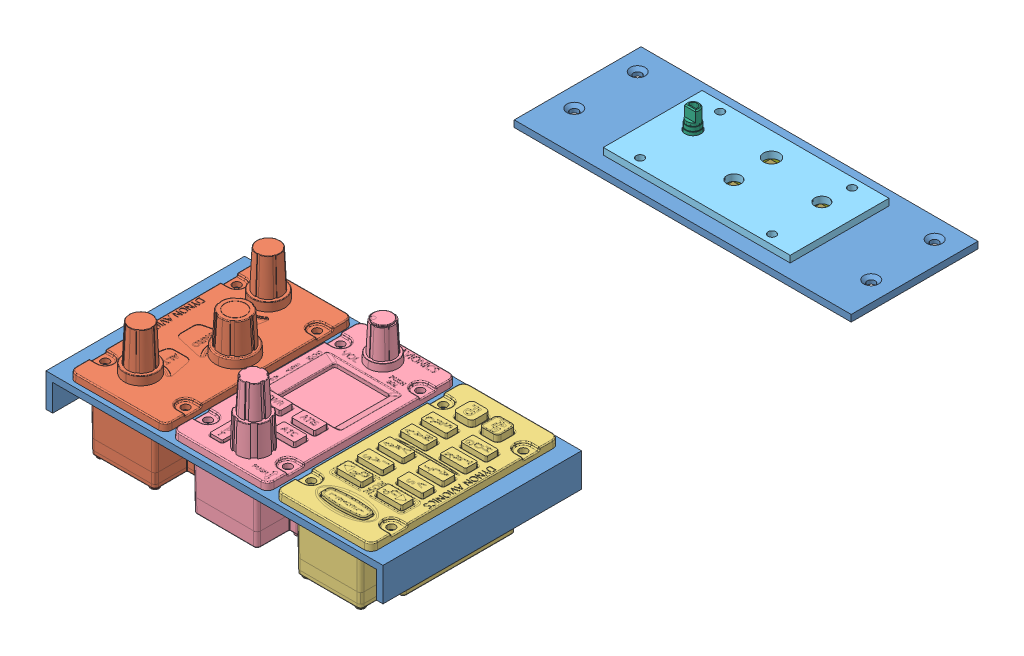
SolidWorks assembly Radio assembly, configuration Default. Lengths in mm.
Overall size (201.11 66.42 309.26).
24 component instances, 17 part files, 8 mates.
Components (placement in the parent):
- Radio stack Bottom-1: Radio stack Bottom [Default] at (52.5504 228.246 225.1405) size (201.11 15.88 309.26)
- SV-KNOB-PANEL_Knob_Control_Panel_Horizontal_Sand_Filled.igs-1: SV-KNOB-PANEL_Knob_Control_Panel_Horizontal_Sand_Filled.igs [Default] at (75.9593 231.421 392.7624) x (0.999994 0 -0.003503) z (0 1 0) size (52.38 89.72 58.92)
- SV-AP-PANEL_Autopilot_Control_Panel_Horizontal_Sand_Filled.igs-1: SV-AP-PANEL_Autopilot_Control_Panel_Horizontal_Sand_Filled.igs [Default] at (174.3711 231.421 393.0909) x (1 0 0) z (0 1 0) size (45.73 89.72 38.5)
- SV-COM-PANEL_Vertical_Solid_Model.igs-1: SV-COM-PANEL_Vertical_Solid_Model.igs [Default] at (101.8389 231.421 437.4175) x (0.999995 0 0.003205) z (0 1 0) size (45.73 89.72 66.42)
- Lighting front plate-1: Lighting front plate [Default] at (52.5504 231.421 225.1405) x (1 0 0) z (0 1 0) size (88.9 46.99 3.17)
- EC12D1524403.step-4: EC12D1524403.step [Default] at (102.1513 226.8481 189.6817) x (1 0 0) z (0 1 0) size (14.15 12.96 20.98)
- untitled.step-1: untitled.step [Default] at (88.9882 225.2956 173.1478) x (0 0 1) z (0 1 0) size (36.53 79.25 3.18)
  - Packages.step-1: Packages.step [Default] at origin size (35.84 78.38 3.18)
    - 78XXL.step-1: 78XXL.step [Default] at (16.51 28.448 -0.0525) x (0 -1 0) z (0 0 -1) size (6.6 3.05 1.47)
    - 32A_ATM.step-1: 32A_ATM.step [Default] at (16.764 58.42 -0.0525) x (0 1 0) z (0 0 -1) size (10.48 11.01 0.1)
    - PINHEADER_2R03_100MIL.step-1: PINHEADER_2R03_100MIL.step [Default] at (4.064 55.626 -0.0525) x (0 -1 0) z (0 0 -1) size (7.77 5.23 0.1)
    - F09V.step-1: F09V.step [Default] at (30.988 66.802 -0.0525) x (0 1 0) z (0 0 -1) size (32.16 12.6 0.1)
    - F09V.step-2: F09V.step [Default] at (30.988 20.574 -0.0525) x (0 1 0) z (0 0 -1) size (32.16 12.6 0.1)
    - C1206.step-1: C1206.step [Default] at (21.082 22.098 -0.0525) x (-1 0 0) z (0 0 -1) size (3.2 1.6 1.3)
    - C1206.step-2: C1206.step [Default] at (21.082 33.528 -0.0525) x (1 0 0) z (0 0 -1) size (3.2 1.6 1.3)
    - EC12S.step-1: EC12S.step [Default] at (15.494 73.66 1.5525) x (0 -1 0) z (0 0 1) size (14.5 14.11 0.1)
    - EC12S.step-2: EC12S.step [Default] at (9.144 43.434 1.5525) x (0 -1 0) z (0 0 1) size (14.5 14.11 0.1)
    - EC12S.step-3: EC12S.step [Default] at (16.256 12.954 1.5525) x (0 -1 0) z (0 0 1) size (14.5 14.11 0.1)
    - EC12S.step-4: EC12S.step [Default] at (27.178 43.688 1.5525) x (0 -1 0) z (0 0 1) size (14.5 14.11 0.1)
  - Board.step-1: Board.step [Default] at origin size (36.32 79.25 1.5)
  - 1-copper.step-1: 1-copper.step [Default] at (0 0 1.5) size (32.74 75.01 0.07)
  - 16-copper.step-1: 16-copper.step [Default] at (0 0 -0.035) size (32.74 75.01 0.07)
  - 1-soldermask.step-1: 1-soldermask.step [Default] at (0 0 1.5) size (36.32 79.25 0.05)
  - 16-soldermask.step-1: 16-soldermask.step [Default] at origin size (36.32 79.25 0.05)
Mates (geometry in assembly coordinates):
- Tangent1: tangent anti-aligned: cylinder of Radio stack Bottom-1 through (95.1191 218.721 424.0962) axis (0 1 0) radius 1.905; face of SV-KNOB-PANEL_Knob_Control_Panel_Horizontal_Sand_Filled.igs-1
- Tangent4: tangent anti-aligned: cylinder of Radio stack Bottom-1 through (143.7918 218.721 424.0962) axis (0 1 0) radius 1.905; edge_curve of SV-COM-PANEL_Vertical_Solid_Model.igs-1
- Tangent5: tangent anti-aligned: cylinder of Radio stack Bottom-1 through (143.7918 218.721 424.0962) axis (0 1 0) radius 1.905; edge_curve of SV-COM-PANEL_Vertical_Solid_Model.igs-1
- Tangent6: tangent anti-aligned: plane of Radio stack Bottom-1 through (52.5504 231.421 225.1405) normal (0 1 0); edge_curve of SV-COM-PANEL_Vertical_Solid_Model.igs-1
- Tangent7: tangent anti-aligned: plane of Radio stack Bottom-1 through (52.5504 231.421 225.1405) normal (0 1 0); edge_curve of SV-KNOB-PANEL_Knob_Control_Panel_Horizontal_Sand_Filled.igs-1
- Tangent9: tangent anti-aligned: plane of Radio stack Bottom-1 through (52.5504 231.421 225.1405) normal (0 1 0); edge_curve of SV-AP-PANEL_Autopilot_Control_Panel_Horizontal_Sand_Filled.igs-1
- Coincident21: coincident anti-aligned: plane of Radio stack Bottom-1 through (52.5504 231.421 225.1405) normal (0 1 0); plane of Lighting front plate-1 through (52.5504 231.421 225.1405) normal (0 -1 0)
- Parallel1: parallel anti-aligned: line of Radio stack Bottom-1 through (105.2871 231.421 215.552) axis (1 0 0); line of untitled.step-1/16-soldermask.step-1 through (172.5542 225.2431 210.2318) axis (-1 0 0)
